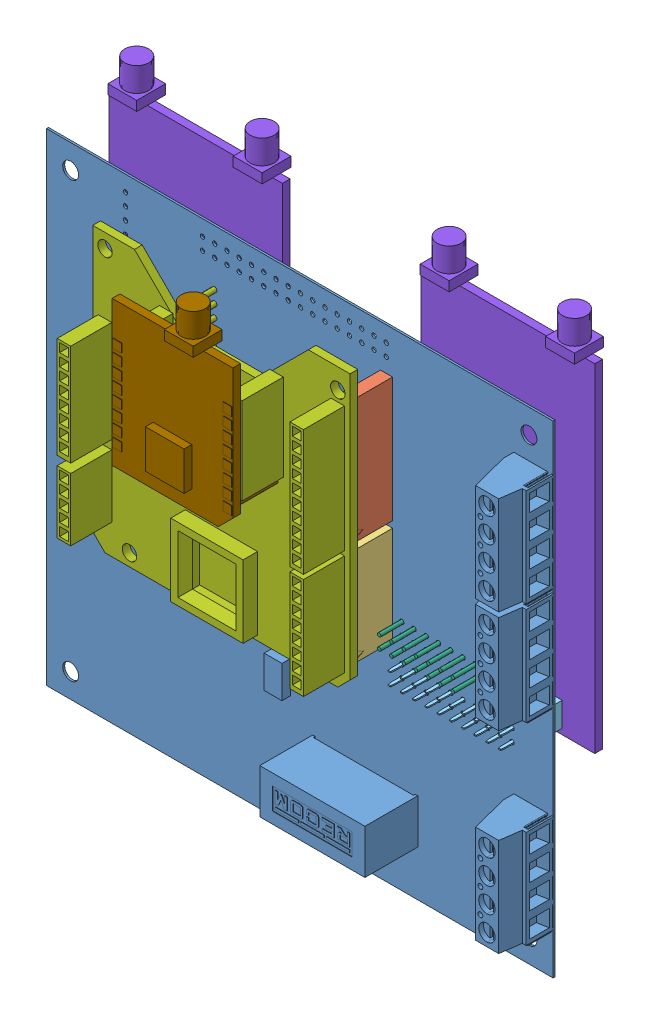
SolidWorks assembly Asfaloth_L2_FC_PCBA, configuration 預設. Lengths in mm.
Overall size (105.09 112.7 35.12).
13 component instances, 9 part files, 36 mates.
Components (placement in the parent):
- Asfaloth_L2_FC_PCB-1: Asfaloth_L2_FC_PCB [預設] at origin size (105.09 100 25.43)
- headerR1x10-1: headerR1x10 [預設] at (73.5584 70.485 0) x (0 1 0) z (0 0 1) size (25.8 2.5 11.9)
- headerR1x8-1: headerR1x8 [預設] at (73.5584 48.641 0) x (0 1 0) z (0 0 1) size (20.32 2.54 11.67)
- headerR1x8-2: headerR1x8 [預設] at (30.3784 66.421 0) x (0 1 0) z (0 0 1) size (20.32 2.54 11.67)
- headerR1x6-1: headerR1x6 [預設] at (30.3784 48.641 0) x (0 1 0) z (0 0 1) size (15.64 2.5 11.9)
- headerR2x10-1: headerR2x10 [預設] at (11.9634 42.926 -8.9115) x (1 0 0) z (0 1 0) size (25.8 11.5 5.04)
- headerR2x10-2: headerR2x10 [預設] at (76.7334 42.926 -8.9115) x (1 0 0) z (0 1 0) size (25.8 11.5 5.04)
- headerR2x7-1: headerR2x7 [預設] at (11.9634 51.816 -0.3115) x (1 0 0) z (0 0 -1) size (17.78 5.04 13.75)
- headerR2x7-2: headerR2x7 [預設] at (76.7334 51.816 -0.3115) x (1 0 0) z (0 0 -1) size (17.78 5.04 13.75)
- Mti-7 development board-2: Mti-7 development board [Default] at (49.4284 64.9266 8.5) x (1 0 0) z (0 -1 0) size (53.34 18.51 57.52)
- LoRa_board-1: LoRa_board [預設] at (25.0634 74.256 -10.5115) x (1 0 0) z (0 -1 0) size (36 8.9 77)
- LoRa_board-2: LoRa_board [預設] at (89.8334 74.256 -10.5115) x (1 0 0) z (0 -1 0) size (36 8.9 77)
- GNSS_board-1: GNSS_board [Default] at (49.3984 85.091 18.61) size (25 37 12.1)
Mates (geometry in assembly coordinates):
- 重合/共線/共點1: coincident anti-aligned: plane of Asfaloth_L2_FC_PCB-1 through (3.073 3.556 0) normal (0 0 1); plane of headerR1x10-1 through (74.8084 69.015 0) normal (0 0 -1)
- 同軸心1: concentric aligned: cylinder of Asfaloth_L2_FC_PCB-1 through (73.5584 93.345 -0.4115) axis (0 0 -1) radius 0.45; circle of headerR1x10-1
- 同軸心2: concentric aligned: cylinder of Asfaloth_L2_FC_PCB-1 through (73.5584 70.485 -0.4115) axis (0 0 -1) radius 0.45; circle of headerR1x10-1
- 同軸心3: concentric anti-aligned: cylinder of Asfaloth_L2_FC_PCB-1 through (73.5584 66.421 -0.4115) axis (0 0 -1) radius 0.45; cylinder of headerR1x8-1 through (73.5584 66.421 -3.17) axis (0 0 1) radius 0.4
- 同軸心4: concentric anti-aligned: cylinder of Asfaloth_L2_FC_PCB-1 through (73.5584 48.641 -0.4115) axis (0 0 -1) radius 0.45; cylinder of headerR1x8-1 through (73.5584 48.641 -3.17) axis (0 0 1) radius 0.4
- 重合/共線/共點2: coincident anti-aligned: plane of Asfaloth_L2_FC_PCB-1 through (3.073 3.556 0) normal (0 0 1); plane of headerR1x8-1 through (74.8284 47.371 0) normal (0 0 -1)
- 同軸心5: concentric anti-aligned: cylinder of Asfaloth_L2_FC_PCB-1 through (30.3784 61.341 -0.4115) axis (0 0 -1) radius 0.45; cylinder of headerR1x6-1 through (30.3784 61.341 -3.25) axis (0 0 1) radius 0.35
- 同軸心6: concentric anti-aligned: cylinder of Asfaloth_L2_FC_PCB-1 through (30.3784 48.641 -0.4115) axis (0 0 -1) radius 0.45; cylinder of headerR1x6-1 through (30.3784 48.641 -3.25) axis (0 0 1) radius 0.35
- 重合/共線/共點3: coincident anti-aligned: plane of Asfaloth_L2_FC_PCB-1 through (3.073 3.556 0) normal (0 0 1); plane of headerR1x6-1 through (31.6284 47.171 0) normal (0 0 -1)
- 同軸心7: concentric anti-aligned: cylinder of Asfaloth_L2_FC_PCB-1 through (30.3784 84.201 -0.4115) axis (0 0 -1) radius 0.45; cylinder of headerR1x8-2 through (30.3784 84.201 -3.17) axis (0 0 1) radius 0.4
- 同軸心8: concentric anti-aligned: cylinder of Asfaloth_L2_FC_PCB-1 through (30.3784 66.421 -0.4115) axis (0 0 -1) radius 0.45; cylinder of headerR1x8-2 through (30.3784 66.421 -3.17) axis (0 0 1) radius 0.4
- 重合/共線/共點4: coincident anti-aligned: plane of Asfaloth_L2_FC_PCB-1 through (3.073 3.556 0) normal (0 0 1); plane of headerR1x8-2 through (31.6484 65.151 0) normal (0 0 -1)
- 同軸心9: concentric anti-aligned: cylinder of Asfaloth_L2_FC_PCB-1 through (11.9634 44.196 -0.4115) axis (0 0 -1) radius 0.45; circle of headerR2x10-1
- 同軸心10: concentric anti-aligned: cylinder of Asfaloth_L2_FC_PCB-1 through (34.8234 44.196 -0.4115) axis (0 0 -1) radius 0.45; circle of headerR2x10-1
- 重合/共線/共點5: coincident anti-aligned: plane of Asfaloth_L2_FC_PCB-1 through (3.073 3.556 -0.4115) normal (0 0 -1); plane of headerR2x10-1 through (11.9634 42.926 -0.4115) normal (0 0 1)
- 同軸心11: concentric anti-aligned: cylinder of Asfaloth_L2_FC_PCB-1 through (99.5934 44.196 -0.4115) axis (0 0 -1) radius 0.45; circle of headerR2x10-2
- 同軸心12: concentric anti-aligned: cylinder of Asfaloth_L2_FC_PCB-1 through (76.7334 44.196 -0.4115) axis (0 0 -1) radius 0.45; circle of headerR2x10-2
- 重合/共線/共點6: coincident anti-aligned: plane of Asfaloth_L2_FC_PCB-1 through (3.073 3.556 -0.4115) normal (0 0 -1); plane of headerR2x10-2 through (76.7334 42.926 -0.4115) normal (0 0 1)
- 同軸心13: concentric aligned: cylinder of Asfaloth_L2_FC_PCB-1 through (11.9634 51.816 -0.4115) axis (0 0 -1) radius 0.45; cylinder of headerR2x7-1 through (11.9634 51.816 4.6885) axis (0 0 -1) radius 0.37
- 同軸心14: concentric aligned: cylinder of Asfaloth_L2_FC_PCB-1 through (27.2034 51.816 -0.4115) axis (0 0 -1) radius 0.45; cylinder of headerR2x7-1 through (27.2034 51.816 4.6885) axis (0 0 -1) radius 0.37
- 重合/共線/共點7: coincident anti-aligned: plane of Asfaloth_L2_FC_PCB-1 through (3.073 3.556 -0.4115) normal (0 0 -1); plane of headerR2x7-1 through (19.5834 50.546 -0.4115) normal (0 0 1)
- 同軸心15: concentric aligned: cylinder of Asfaloth_L2_FC_PCB-1 through (91.9734 51.816 -0.4115) axis (0 0 -1) radius 0.45; cylinder of headerR2x7-2 through (91.9734 51.816 4.6885) axis (0 0 -1) radius 0.37
- 同軸心16: concentric aligned: cylinder of Asfaloth_L2_FC_PCB-1 through (76.7334 51.816 -0.4115) axis (0 0 -1) radius 0.45; cylinder of headerR2x7-2 through (76.7334 51.816 4.6885) axis (0 0 -1) radius 0.37
- 重合/共線/共點8: coincident anti-aligned: plane of Asfaloth_L2_FC_PCB-1 through (3.073 3.556 -0.4115) normal (0 0 -1); plane of headerR2x7-2 through (84.3534 50.546 -0.4115) normal (0 0 1)
- 同軸心17: concentric anti-aligned: cylinder of headerR1x8-1 through (73.5584 48.641 1.7) axis (0 0 1) radius 0.4; cylinder of Mti-7 development board-2 through (73.5584 48.641 10.1) axis (0 0 -1) radius 0.5
- 同軸心19: concentric anti-aligned: cylinder of Asfaloth_L2_FC_PCB-1 through (11.9634 41.656 -0.4115) axis (0 0 -1) radius 0.45; cylinder of LoRa_board-1 through (11.9634 41.656 -8.8115) axis (0 0 1) radius 0.5
- 同軸心20: concentric anti-aligned: cylinder of Asfaloth_L2_FC_PCB-1 through (34.8234 41.656 -0.4115) axis (0 0 -1) radius 0.45; cylinder of LoRa_board-1 through (34.8234 41.656 -8.8115) axis (0 0 1) radius 0.5
- 重合/共線/共點9: coincident anti-aligned: plane of headerR2x10-1 through (11.9634 42.926 -8.9115) normal (0 0 -1); plane of LoRa_board-1 through (25.0634 74.256 -8.9115) normal (0 0 1)
- 同軸心21: concentric anti-aligned: cylinder of Asfaloth_L2_FC_PCB-1 through (76.7334 41.656 -0.4115) axis (0 0 -1) radius 0.45; cylinder of LoRa_board-2 through (76.7334 41.656 -8.8115) axis (0 0 1) radius 0.5
- 同軸心22: concentric anti-aligned: cylinder of Asfaloth_L2_FC_PCB-1 through (99.5934 41.656 -0.4115) axis (0 0 -1) radius 0.45; cylinder of LoRa_board-2 through (99.5934 41.656 -8.8115) axis (0 0 1) radius 0.5
- 重合/共線/共點10: coincident anti-aligned: plane of headerR2x10-2 through (76.7334 42.926 -8.9115) normal (0 0 -1); plane of LoRa_board-2 through (89.8334 74.256 -8.9115) normal (0 0 1)
- 重合/共線/共點11: coincident anti-aligned: plane of headerR1x8-1 through (74.8284 47.371 8.5) normal (0 0 1); plane of Mti-7 development board-2 through (49.4284 72.321 8.5) normal (0 0 -1)
- 同軸心23: concentric anti-aligned: circle of Asfaloth_L2_FC_PCB-1; cylinder of Mti-7 development board-2 through (73.5584 93.345 10.1) axis (0 0 -1) radius 0.5
- 同軸心24: concentric: cylinder of Mti-7 development board-2 through (37.9984 92.191 10.1) axis (0 0 -1) radius 0.5; cylinder of GNSS_board-1 through (37.9984 92.191 10.31) axis (0 0 1) radius 0.5
- 同軸心25: concentric: cylinder of Mti-7 development board-2 through (60.8584 92.191 10.1) axis (0 0 -1) radius 0.5; cylinder of GNSS_board-1 through (60.8584 92.191 10.31) axis (0 0 1) radius 0.5
- 重合/共線/共點13: coincident anti-aligned: plane of Mti-7 development board-2 through (37.9984 84.591 18.61) normal (0 0 1); plane of GNSS_board-1 through (49.3984 85.091 18.61) normal (0 0 -1)
